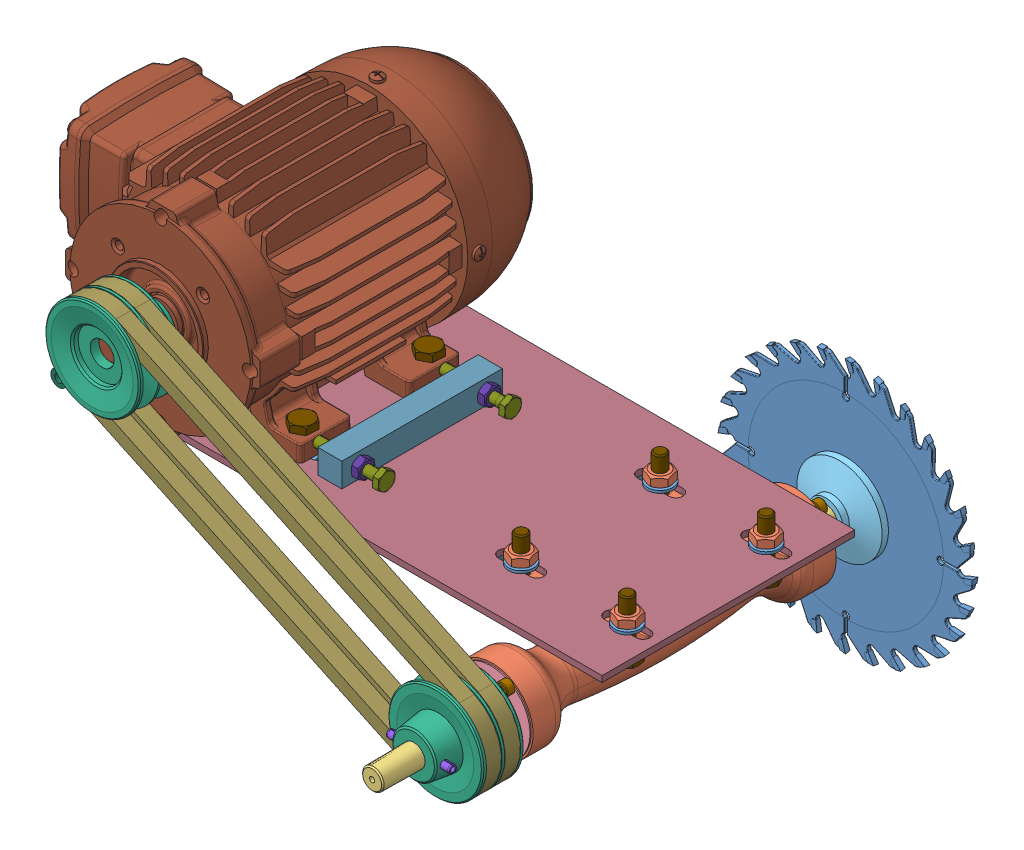
SolidWorks assembly Serra circular de bancada, configuration Default. Lengths in mm.
Overall size (508.56 311.6 431.24).
60 component instances, 20 part files, 92 mates.
Components (placement in the parent):
- cirsaw-1: cirsaw [Default] at (-60.7832 8.4139 49.2774) size (202.41 202.41 3.87)
- Eixo Serra Circular 5-8 N1-1: Eixo Serra Circular 5-8 N1 [Valor predeterminado] at (-60.7832 8.4139 212.2774) x (0 0 -1) z (-1 0 0) size (431.24 80.12 104.06)
  - Base Principal-1: Base Principal [Valor predeterminado] at origin size (240 75.12 104.06)
  - Eixo Principal-1: Eixo Principal [Valor predeterminado] at (9 0 0) size (431.24 28 28)
  - Tampa Rolamento-1: Tampa Rolamento [Valor predeterminado] at (121.5 0 0) x (0 0 1) z (-1 0 0) size (62 62 3)
  - Tampa Rolamento-2: Tampa Rolamento [Valor predeterminado] at (-121.5 0 0) x (0 0 1) z (1 0 0) size (62 62 3)
  - Suporte Principal-1: Suporte Principal [Valor predeterminado] at (152 0 0) size (16 67.5 67.5)
  - Suporte Principal-2: Suporte Principal [Valor predeterminado] at (171 0 0) x (-1 0 0) z (0 0 -1) size (16 67.5 67.5)
  - Polia Correa Dupla-1: Polia Correa Dupla [Valor predeterminado] at (-157 0 0) size (50 75 75)
  - angular contact ball bearing_68_skf_SKF - 7204 BE - 10,DE,AC,10_68-1: angular contact ball bearing_68_skf_SKF - 7204 BE - 10,DE,AC,10_68 [Valor predeterminado] at (113 0 0) size (14 47 47)
  - angular contact ball bearing_68_skf_SKF - 7204 BE - 10,DE,AC,10_68-2: angular contact ball bearing_68_skf_SKF - 7204 BE - 10,DE,AC,10_68 [Valor predeterminado] at (-113 0 0) size (14 47 47)
  - spring pin slotted_hd_din_Spring Pin ISO 8752 - 6 x 50 - N - St-1: spring pin slotted_hd_din_Spring Pin ISO 8752 - 6 x 50 - N - St [Valor predeterminado] at (-176 0 25) x (0 0 -1) z (0 -1 0) size (50 6 5.99)
  - socket head cap screw_am_B18.3.1M - 6 x 1.0 x 16 Hex SHCS -- 16SHX-1: socket head cap screw_am_B18.3.1M - 6 x 1.0 x 16 Hex SHCS -- 16SHX [Valor predeterminado] at (127 24.2487 -14) x (-1 0 0) z (0 0.924225 0.381849) size (22 10 10)
  - socket head cap screw_am_B18.3.1M - 6 x 1.0 x 16 Hex SHCS -- 16SHX-2: socket head cap screw_am_B18.3.1M - 6 x 1.0 x 16 Hex SHCS -- 16SHX [Valor predeterminado] at (127 0 28) x (-1 0 0) z (0 0.924225 0.381849) size (22 10 10)
  - socket head cap screw_am_B18.3.1M - 6 x 1.0 x 16 Hex SHCS -- 16SHX-3: socket head cap screw_am_B18.3.1M - 6 x 1.0 x 16 Hex SHCS -- 16SHX [Valor predeterminado] at (127 -24.2487 -14) x (-1 0 0) z (0 0.924225 0.381849) size (22 10 10)
  - socket head cap screw_am_B18.3.1M - 6 x 1.0 x 16 Hex SHCS -- 16SHX-4: socket head cap screw_am_B18.3.1M - 6 x 1.0 x 16 Hex SHCS -- 16SHX [Valor predeterminado] at (-127 24.2487 -14) size (22 10 10)
  - socket head cap screw_am_B18.3.1M - 6 x 1.0 x 16 Hex SHCS -- 16SHX-5: socket head cap screw_am_B18.3.1M - 6 x 1.0 x 16 Hex SHCS -- 16SHX [Valor predeterminado] at (-127 0 28) size (22 10 10)
  - socket head cap screw_am_B18.3.1M - 6 x 1.0 x 16 Hex SHCS -- 16SHX-6: socket head cap screw_am_B18.3.1M - 6 x 1.0 x 16 Hex SHCS -- 16SHX [Valor predeterminado] at (-127 -24.2487 -14) size (22 10 10)
  - hex nut heavy_am_B18.2.4.6M - Heavy hex nut,  M16 x 2 --D-S-1: hex nut heavy_am_B18.2.4.6M - Heavy hex nut,  M16 x 2 --D-S [Valor predeterminado] at (179 0 0) x (0 1 0) z (-1 0 0) size (27 31.18 17.1)
- Motor IEC  W21_GENERAL_PURPOSE  03_FRAME_80  WITH_FLANG-1: Motor IEC  W21_GENERAL_PURPOSE  03_FRAME_80  WITH_FLANG [Valor predeterminado] at (-332.4526 135.6764 223.2774) x (0 0 1) z (-1 0 0) size (300.91 163.14 218.82)
- Polia Correa Dupla-1: Polia Correa Dupla [Valor predeterminado] at (-332.4526 135.6764 352.2774) x (0 0 1) z (0 1 0) size (50 75 75)
- Correia-1: Correia [Predeterminada] at (-196.6179 72.0451 368.2774) x (0.905565 -0.424208 0) z (0 0 1) size (375 75 12)
- Correia-3: Correia [Predeterminada] at (-196.6179 72.0451 353.2774) x (0.905565 -0.424208 0) z (0 0 1) size (375 75 12)
- Base motor e eixo-1: Base motor e eixo [Predeterminada] at (-208.7832 55.6764 212.2774) x (-1 0 0) z (0 -1 0) size (430 200 4.76)
- Esticador do motor-1: Esticador do motor [Predeterminada] at (-234.2582 65.2014 223.7774) size (19.05 19.05 127)
- Gonzo fêmea-1: Gonzo fêmea [Valor predeterminado] at (-423.7832 44.5639 127.2774) x (1 0 0) z (0 0 -1) size (26.35 12.7 30)
- Gonzo fêmea-3: Gonzo fêmea [Valor predeterminado] at (-423.7832 44.5639 297.2774) x (1 0 0) z (0 0 -1) size (26.35 12.7 30)
- parafuso sextavado din 931-1 - m8 x 50-1: parafuso sextavado din 931-1 - m8 x 50 [Valor predeterminado] at (-207.9526 65.2014 273.7774) x (-1 0 0) z (0 0.832935 -0.553371) size (55.3 15.01 13)
- parafuso sextavado din 931-1 - m8 x 50-3: parafuso sextavado din 931-1 - m8 x 50 [Valor predeterminado] at (-207.9526 65.2014 173.7774) x (-1 0 0) z (0 0.832935 -0.553371) size (55.3 15.01 13)
- porca sextavada din 555-5 - m8-1: porca sextavada din 555-5 - m8 [Valor predeterminado] at (-224.7332 65.2014 173.7774) size (6.64 15.01 13)
- porca sextavada din 555-5 - m8-3: porca sextavada din 555-5 - m8 [Valor predeterminado] at (-224.7332 65.2014 273.7774) size (6.64 15.01 13)
- parafuso sextavado din 931-1 - m10 x 40-1: parafuso sextavado din 931-1 - m10 x 40 [Valor predeterminado] at (-269.9526 68.6764 173.2774) x (0 -1 0) z (0.546944 0 -0.837169) size (46.4 19.63 17)
- arruela lisa din 125 - a 10,5-1: arruela lisa din 125 - a 10,5 [Valor predeterminado] at (-269.9526 50.9139 173.2774) x (0 -1 0) z (0 0 1) size (2 20 20)
- porca sextavada din 555-5 - m10-1: porca sextavada din 555-5 - m10 [Valor predeterminado] at (-269.9526 48.9139 173.2774) x (0 -1 0) z (0 0 1) size (8 19.63 17)
- parafuso sextavado din 931-1 - m10 x 40-3: parafuso sextavado din 931-1 - m10 x 40 [Valor predeterminado] at (-269.9526 68.6764 273.2774) x (0 -1 0) z (0.546944 0 -0.837169) size (46.4 19.63 17)
- parafuso sextavado din 931-1 - m10 x 40-5: parafuso sextavado din 931-1 - m10 x 40 [Valor predeterminado] at (-394.9526 68.6764 173.2774) x (0 -1 0) z (0.983409 0 -0.181404) size (46.4 19.63 17)
- parafuso sextavado din 931-1 - m10 x 40-7: parafuso sextavado din 931-1 - m10 x 40 [Valor predeterminado] at (-394.9526 68.6764 273.2774) x (0 -1 0) z (0.546944 0 -0.837169) size (46.4 19.63 17)
- porca sextavada din 555-5 - m10-3: porca sextavada din 555-5 - m10 [Valor predeterminado] at (-394.9526 48.9139 173.2774) x (0 -1 0) z (0 0 1) size (8 19.63 17)
- porca sextavada din 555-5 - m10-5: porca sextavada din 555-5 - m10 [Valor predeterminado] at (-269.9526 48.9139 273.2774) x (0 -1 0) z (-0.269704 0 0.962943) size (8 19.63 17)
- porca sextavada din 555-5 - m10-7: porca sextavada din 555-5 - m10 [Valor predeterminado] at (-394.9526 48.9139 273.2774) x (0 -1 0) z (0 0 1) size (8 19.63 17)
- arruela lisa din 125 - a 10,5-3: arruela lisa din 125 - a 10,5 [Valor predeterminado] at (-394.9526 50.9139 173.2774) x (0 -1 0) z (0 0 1) size (2 20 20)
- arruela lisa din 125 - a 10,5-5: arruela lisa din 125 - a 10,5 [Valor predeterminado] at (-394.9526 50.9139 273.2774) x (0 -1 0) z (0 0 1) size (2 20 20)
- arruela lisa din 125 - a 10,5-7: arruela lisa din 125 - a 10,5 [Valor predeterminado] at (-269.9526 50.9139 273.2774) x (0 -1 0) z (0 0 1) size (2 20 20)
- Esticador do motor-3: Esticador do motor [Predeterminada] at (-133.3082 41.3889 212.2774) size (19.05 19.05 127)
- parafuso sextavado din 931-1 - m8 x 50-5: parafuso sextavado din 931-1 - m8 x 50 [Valor predeterminado] at (-162.7832 41.3889 162.2774) x (1 0 0) z (0 -0.387923 0.921692) size (55.3 15.01 13)
- porca sextavada din 555-5 - m8-5: porca sextavada din 555-5 - m8 [Valor predeterminado] at (-142.8332 41.3889 162.2774) x (-1 0 0) z (0 -0.924225 -0.381849) size (6.64 15.01 13)
- porca sextavada din 555-5 - m8-7: porca sextavada din 555-5 - m8 [Valor predeterminado] at (-142.8332 41.3889 262.2774) x (-1 0 0) z (0 -0.924225 -0.381849) size (6.64 15.01 13)
- parafuso sextavado din 931-1 - m8 x 50-7: parafuso sextavado din 931-1 - m8 x 50 [Valor predeterminado] at (-162.7832 41.3889 262.2774) x (1 0 0) z (0 -0.387923 0.921692) size (55.3 15.01 13)
- parafuso sextavado din 931-1 - m10 x 40-9: parafuso sextavado din 931-1 - m10 x 40 [Valor predeterminado] at (-18.7832 37.9139 267.2774) x (0 1 0) z (-0.999339 0 0.03636) size (46.4 19.63 17)
- parafuso sextavado din 931-1 - m10 x 40-11: parafuso sextavado din 931-1 - m10 x 40 [Valor predeterminado] at (-102.7832 37.9139 157.2774) x (0 1 0) z (0.414075 0 -0.910243) size (46.4 19.63 17)
- parafuso sextavado din 931-1 - m10 x 40-13: parafuso sextavado din 931-1 - m10 x 40 [Valor predeterminado] at (-102.7832 37.9139 267.2774) x (0 1 0) z (-0.996636 0 0.08195) size (46.4 19.63 17)
- parafuso sextavado din 931-1 - m10 x 40-15: parafuso sextavado din 931-1 - m10 x 40 [Valor predeterminado] at (-18.7832 37.9139 157.2774) x (0 1 0) z (-0.887169 0 0.461445) size (46.4 19.63 17)
- porca sextavada din 555-5 - m10-9: porca sextavada din 555-5 - m10 [Valor predeterminado] at (-18.7832 57.6764 267.2774) x (0 1 0) z (0.300888 0 -0.95366) size (8 19.63 17)
- porca sextavada din 555-5 - m10-11: porca sextavada din 555-5 - m10 [Valor predeterminado] at (-102.7832 57.6764 267.2774) x (0 1 0) z (0.300888 0 -0.95366) size (8 19.63 17)
- porca sextavada din 555-5 - m10-13: porca sextavada din 555-5 - m10 [Valor predeterminado] at (-102.7832 57.6764 157.2774) x (0 1 0) z (0.300888 0 -0.95366) size (8 19.63 17)
- porca sextavada din 555-5 - m10-15: porca sextavada din 555-5 - m10 [Valor predeterminado] at (-18.7832 57.6764 157.2774) x (0 1 0) z (0.300888 0 -0.95366) size (8 19.63 17)
- arruela lisa din 125 - a 10,5-9: arruela lisa din 125 - a 10,5 [Valor predeterminado] at (-102.7832 57.6764 157.2774) x (0 -1 0) z (0 0 1) size (2 20 20)
- arruela lisa din 125 - a 10,5-11: arruela lisa din 125 - a 10,5 [Valor predeterminado] at (-102.7832 57.6764 267.2774) x (0 -1 0) z (0 0 1) size (2 20 20)
- arruela lisa din 125 - a 10,5-13: arruela lisa din 125 - a 10,5 [Valor predeterminado] at (-18.7832 57.6764 267.2774) x (0 -1 0) z (0 0 1) size (2 20 20)
- arruela lisa din 125 - a 10,5-15: arruela lisa din 125 - a 10,5 [Valor predeterminado] at (-18.7832 57.6764 157.2774) x (0 -1 0) z (0 0 1) size (2 20 20)
Mates (geometry in assembly coordinates):
- Concêntrico1: concentric anti-aligned: cylinder of Motor IEC  W21_GENERAL_PURPOSE  03_FRAME_80  WITH_FLANG-1 through (-332.4526 135.6764 363.2774) axis (0 0 1) radius 9.5; cone of Polia Correa Dupla-1 through (-332.4526 135.6764 327.2774) axis (0 0 -1)
- Coincidente3: coincident anti-aligned: plane of Motor IEC  W21_GENERAL_PURPOSE  03_FRAME_80  WITH_FLANG-1 through (-332.4526 173.7764 327.2774) normal (0 0 1); plane of Polia Correa Dupla-1 through (-348.9872 152.211 327.2774) normal (0 0 -1)
- Paralelo1: parallel aligned: plane of Motor IEC  W21_GENERAL_PURPOSE  03_FRAME_80  WITH_FLANG-1 through (-332.4526 141.6764 332.2774) normal (0 1 0); plane of Polia Correa Dupla-1 through (-332.4526 135.6764 352.2774) normal (0 1 0)
- Coincidente5: coincident aligned: plane of Eixo Serra Circular 5-8 N1-1/Polia Correa Dupla-1 through (-97.7212 45.3519 377.2774) normal (0 0 1); plane of Polia Correa Dupla-1 through (-369.3906 98.7384 377.2774) normal (0 0 1)
- Concêntrico3: concentric anti-aligned: cylinder of cirsaw-1 through (-60.7832 8.4139 52.2774) axis (0 0 -1) radius 11; cylinder of Eixo Serra Circular 5-8 N1-1/Eixo Principal-1 through (-60.7832 8.4139 40.7382) axis (0 0 1) radius 8
- Coincidente6: coincident anti-aligned: plane of cirsaw-1 through (-60.7832 8.4139 52.2774) normal (0 0 1); plane of Eixo Serra Circular 5-8 N1-1/Suporte Principal-1 through (-26.6282 42.5689 52.2774) normal (0 0 -1)
- Concêntrico4: concentric anti-aligned: cylinder of Eixo Serra Circular 5-8 N1-1/Polia Correa Dupla-1 through (-60.7832 8.4139 365.5274) axis (0 0 1) radius 23.5; cylinder of Correia-1 through (-60.7832 8.4139 374.2774) axis (0 0 -1) radius 27.5
- Coincidente7: coincident anti-aligned: circle of Eixo Serra Circular 5-8 N1-1/Polia Correa Dupla-1; plane of Correia-1 through (-332.4526 135.6764 374.2774) normal (0 0 1)
- Concêntrico5: concentric aligned: cylinder of Polia Correa Dupla-1 through (-332.4526 135.6764 370.5274) axis (0 0 -1) radius 23.5; cylinder of Correia-1 through (-332.4526 135.6764 374.2774) axis (0 0 -1) radius 37.5
- Concêntrico6: concentric anti-aligned: cylinder of Eixo Serra Circular 5-8 N1-1/Polia Correa Dupla-1 through (-60.7832 8.4139 351.0274) axis (0 0 1) radius 23.5; cylinder of Correia-3 through (-60.7832 8.4139 359.2774) axis (0 0 -1) radius 27.5
- Coincidente8: coincident anti-aligned: circle of Eixo Serra Circular 5-8 N1-1/Polia Correa Dupla-1; plane of Correia-3 through (-332.4526 135.6764 347.2774) normal (0 0 -1)
- Coincidente9: coincident aligned: plane of Correia-1 through (-348.3604 101.7177 374.2774) normal (-0.424208 -0.905565 0); plane of Correia-3 through (-348.3604 101.7177 359.2774) normal (-0.424208 -0.905565 0)
- Paralelo2: parallel anti-aligned: plane of Eixo Serra Circular 5-8 N1-1/Base Principal-1 through (-10.7832 37.9139 170.0101) normal (0 -1 0); plane of assembly through (0 0 0) normal (0 1 0)
- Coincidente11: coincident anti-aligned: plane of Eixo Serra Circular 5-8 N1-1/Base Principal-1 through (-10.7832 50.9139 144.2774) normal (0 1 0); plane of Base motor e eixo-1 through (-208.7832 50.9139 212.2774) normal (0 -1 0)
- Coincidente13: coincident anti-aligned: plane of Motor IEC  W21_GENERAL_PURPOSE  03_FRAME_80  WITH_FLANG-1 through (-406.9526 55.6764 159.7774) normal (0 -1 0); plane of Base motor e eixo-1 through (-208.7832 55.6764 212.2774) normal (0 1 0)
- Coincidente14: coincident aligned: plane of Eixo Serra Circular 5-8 N1-1/Base Principal-1; plane of Base motor e eixo-1 through (-208.7832 55.6764 267.2774) normal (0 0 -1)
- Distância1: distance = 15 mm aligned: plane of Base motor e eixo-1 through (6.2168 50.9139 312.2774) normal (1 0 0); plane of Eixo Serra Circular 5-8 N1-1/Base Principal-1 through (-8.7832 48.9139 149.9199) normal (1 0 0)
- Coincidente16: coincident anti-aligned: plane of Base motor e eixo-1 through (-208.7832 55.6764 212.2774) normal (0 1 0); plane of Esticador do motor-1 through (-243.7832 55.6764 287.2774) normal (0 -1 0)
- Distância2: distance = 25 mm aligned: plane of Esticador do motor-1 through (-234.2582 65.2014 287.2774) normal (0 0 1); plane of Base motor e eixo-1 through (6.2168 50.9139 312.2774) normal (0 0 1)
- Distância3: distance = 180 mm aligned: plane of Esticador do motor-1 through (-243.7832 55.6764 287.2774) normal (-1 0 0); plane of Base motor e eixo-1 through (-423.7832 50.9139 312.2774) normal (-1 0 0)
- Coincidente17: coincident anti-aligned: plane of Base motor e eixo-1 through (-208.7832 50.9139 212.2774) normal (0 -1 0); plane of Gonzo fêmea-1 through (-423.7832 50.9139 162.5162) normal (0 1 0)
- Coincidente19: coincident aligned: plane of Base motor e eixo-1 through (6.2168 50.9139 112.2774) normal (0 0 -1); plane of Gonzo fêmea-1 through (-423.7832 44.5639 112.2774) normal (0 0 -1)
- Coincidente20: coincident anti-aligned: plane of Base motor e eixo-1 through (-423.7832 50.9139 312.2774) normal (-1 0 0); plane of Gonzo fêmea-1
- Concêntrico7: concentric aligned: cylinder of Gonzo fêmea-1 through (-423.7832 44.5639 112.2774) axis (0 0 1) radius 6.35; cylinder of Gonzo fêmea-3 through (-423.7832 44.5639 282.2774) axis (0 0 1) radius 6.35
- Coincidente22: coincident aligned: plane of Base motor e eixo-1 through (6.2168 50.9139 312.2774) normal (0 0 1); plane of Gonzo fêmea-3 through (-423.7832 44.5639 312.2774) normal (0 0 1)
- Concêntrico8: concentric anti-aligned: cylinder of Esticador do motor-1 through (-224.7332 65.2014 273.7774) axis (1 0 0) radius 3.4; cylinder of parafuso sextavado din 931-1 - m8 x 50-1 through (-246.9526 65.2014 273.7774) axis (-1 0 0) radius 4
- Coincidente23: coincident anti-aligned: plane of Motor IEC  W21_GENERAL_PURPOSE  03_FRAME_80  WITH_FLANG-1 through (-257.9526 55.6764 286.7774) normal (1 0 0); plane of parafuso sextavado din 931-1 - m8 x 50-1 through (-257.9526 66.3081 275.4433) normal (-1 0 0)
- Concêntrico9: concentric anti-aligned: cylinder of Esticador do motor-1 through (-224.7332 65.2014 173.7774) axis (1 0 0) radius 3.4; cylinder of parafuso sextavado din 931-1 - m8 x 50-3 through (-246.9526 65.2014 173.7774) axis (-1 0 0) radius 4
- Coincidente24: coincident aligned: plane of parafuso sextavado din 931-1 - m8 x 50-1 through (-202.6525 65.2014 273.7774) normal (1 0 0); plane of parafuso sextavado din 931-1 - m8 x 50-3 through (-202.6525 65.2014 173.7774) normal (1 0 0)
- Coincidente25: coincident anti-aligned: plane of Esticador do motor-1 through (-224.7332 55.6764 287.2774) normal (1 0 0); plane of porca sextavada din 555-5 - m8-1 through (-224.7332 65.2014 173.7774) normal (-1 0 0)
- Concêntrico11: concentric anti-aligned: cylinder of parafuso sextavado din 931-1 - m8 x 50-3 through (-246.9526 65.2014 173.7774) axis (-1 0 0) radius 4; cylinder of porca sextavada din 555-5 - m8-1 through (-239.1716 65.2014 173.7774) axis (1 0 0) radius 3.3235
- Coincidente26: coincident anti-aligned: plane of Esticador do motor-1 through (-224.7332 55.6764 287.2774) normal (1 0 0); plane of porca sextavada din 555-5 - m8-3 through (-224.7332 65.2014 273.7774) normal (-1 0 0)
- Concêntrico12: concentric anti-aligned: cylinder of parafuso sextavado din 931-1 - m8 x 50-1 through (-246.9526 65.2014 273.7774) axis (-1 0 0) radius 4; cylinder of porca sextavada din 555-5 - m8-3 through (-239.1716 65.2014 273.7774) axis (1 0 0) radius 3.3235
- Concêntrico13: concentric aligned: cylinder of Motor IEC  W21_GENERAL_PURPOSE  03_FRAME_80  WITH_FLANG-1 through (-269.9526 212.4789 173.2774) axis (0 -1 0) radius 5; cylinder of parafuso sextavado din 931-1 - m10 x 40-1 through (-269.9526 41.6764 173.2774) axis (0 -1 0) radius 5
- Coincidente27: coincident anti-aligned: plane of Motor IEC  W21_GENERAL_PURPOSE  03_FRAME_80  WITH_FLANG-1 through (-257.9526 68.6764 159.7774) normal (0 1 0); plane of parafuso sextavado din 931-1 - m10 x 40-1 through (-275.3104 68.6764 169.777) normal (0 -1 0)
- Coincidente28: coincident anti-aligned: plane of Base motor e eixo-1 through (-208.7832 50.9139 212.2774) normal (0 -1 0); plane of arruela lisa din 125 - a 10,5-1 through (-269.9526 50.9139 173.2774) normal (0 1 0)
- Concêntrico14: concentric aligned: cylinder of parafuso sextavado din 931-1 - m10 x 40-1 through (-269.9526 41.6764 173.2774) axis (0 -1 0) radius 5; cylinder of arruela lisa din 125 - a 10,5-1 through (-269.9526 50.9139 173.2774) axis (0 -1 0) radius 5.25
- Coincidente29: coincident anti-aligned: plane of arruela lisa din 125 - a 10,5-1 through (-269.9526 48.9139 173.2774) normal (0 -1 0); plane of porca sextavada din 555-5 - m10-1 through (-269.9526 48.9139 173.2774) normal (0 1 0)
- Concêntrico15: concentric aligned: cylinder of parafuso sextavado din 931-1 - m10 x 40-1 through (-269.9526 41.6764 173.2774) axis (0 -1 0) radius 5; cylinder of porca sextavada din 555-5 - m10-1 through (-269.9526 68.0862 173.2774) axis (0 -1 0) radius 4.188
- Concêntrico16: concentric aligned: cylinder of Motor IEC  W21_GENERAL_PURPOSE  03_FRAME_80  WITH_FLANG-1 through (-394.9526 212.4789 173.2774) axis (0 -1 0) radius 5; cylinder of parafuso sextavado din 931-1 - m10 x 40-5 through (-394.9526 41.6764 173.2774) axis (0 -1 0) radius 5
- Coincidente30: coincident aligned: plane of parafuso sextavado din 931-1 - m10 x 40-1 through (-269.9526 75.0765 173.2774) normal (0 1 0); plane of parafuso sextavado din 931-1 - m10 x 40-5 through (-394.9526 75.0765 173.2774) normal (0 1 0)
- Coincidente31: coincident aligned: plane of parafuso sextavado din 931-1 - m10 x 40-3 through (-269.9526 75.0765 273.2774) normal (0 1 0); plane of parafuso sextavado din 931-1 - m10 x 40-7 through (-394.9526 75.0765 273.2774) normal (0 1 0)
- Coincidente32: coincident aligned: plane of parafuso sextavado din 931-1 - m10 x 40-3 through (-269.9526 75.0765 273.2774) normal (0 1 0); plane of parafuso sextavado din 931-1 - m10 x 40-5 through (-394.9526 75.0765 173.2774) normal (0 1 0)
- Concêntrico17: concentric aligned: cylinder of Motor IEC  W21_GENERAL_PURPOSE  03_FRAME_80  WITH_FLANG-1 through (-394.9526 212.4789 273.2774) axis (0 -1 0) radius 5; cylinder of parafuso sextavado din 931-1 - m10 x 40-7 through (-394.9526 41.6764 273.2774) axis (0 -1 0) radius 5
- Concêntrico18: concentric aligned: cylinder of Motor IEC  W21_GENERAL_PURPOSE  03_FRAME_80  WITH_FLANG-1 through (-269.9526 212.4789 273.2774) axis (0 -1 0) radius 5; cylinder of parafuso sextavado din 931-1 - m10 x 40-3 through (-269.9526 41.6764 273.2774) axis (0 -1 0) radius 5
- Concêntrico19: concentric aligned: cylinder of parafuso sextavado din 931-1 - m10 x 40-5 through (-394.9526 41.6764 173.2774) axis (0 -1 0) radius 5; cylinder of arruela lisa din 125 - a 10,5-3 through (-394.9526 50.9139 173.2774) axis (0 -1 0) radius 5.25
- Coincidente33: coincident anti-aligned: plane of Base motor e eixo-1 through (-208.7832 50.9139 212.2774) normal (0 -1 0); plane of arruela lisa din 125 - a 10,5-3 through (-394.9526 50.9139 173.2774) normal (0 1 0)
- Coincidente34: coincident aligned: plane of arruela lisa din 125 - a 10,5-5 through (-394.9526 48.9139 273.2774) normal (0 -1 0); plane of arruela lisa din 125 - a 10,5-7 through (-269.9526 48.9139 273.2774) normal (0 -1 0)
- Coincidente35: coincident aligned: plane of arruela lisa din 125 - a 10,5-3 through (-394.9526 48.9139 173.2774) normal (0 -1 0); plane of arruela lisa din 125 - a 10,5-5 through (-394.9526 48.9139 273.2774) normal (0 -1 0)
- Concêntrico20: concentric aligned: cylinder of parafuso sextavado din 931-1 - m10 x 40-7 through (-394.9526 41.6764 273.2774) axis (0 -1 0) radius 5; cylinder of arruela lisa din 125 - a 10,5-5 through (-394.9526 50.9139 273.2774) axis (0 -1 0) radius 5.25
- Concêntrico21: concentric aligned: cylinder of parafuso sextavado din 931-1 - m10 x 40-3 through (-269.9526 41.6764 273.2774) axis (0 -1 0) radius 5; cylinder of arruela lisa din 125 - a 10,5-7 through (-269.9526 50.9139 273.2774) axis (0 -1 0) radius 5.25
- Concêntrico22: concentric aligned: cylinder of parafuso sextavado din 931-1 - m10 x 40-5 through (-394.9526 41.6764 173.2774) axis (0 -1 0) radius 5; cylinder of porca sextavada din 555-5 - m10-3 through (-394.9526 68.0862 173.2774) axis (0 -1 0) radius 4.188
- Concêntrico23: concentric aligned: cylinder of parafuso sextavado din 931-1 - m10 x 40-3 through (-269.9526 41.6764 273.2774) axis (0 -1 0) radius 5; cylinder of porca sextavada din 555-5 - m10-5 through (-269.9526 68.0862 273.2774) axis (0 -1 0) radius 4.188
- Concêntrico24: concentric aligned: cylinder of parafuso sextavado din 931-1 - m10 x 40-7 through (-394.9526 41.6764 273.2774) axis (0 -1 0) radius 5; cylinder of porca sextavada din 555-5 - m10-7 through (-394.9526 68.0862 273.2774) axis (0 -1 0) radius 4.188
- Largura1: width aligned: plane of porca sextavada din 555-5 - m10-5 through (-269.9526 40.9139 273.2774) normal (0 -1 0); plane of porca sextavada din 555-5 - m10-1 through (-269.9526 40.9139 173.2774) normal (0 -1 0); plane of porca sextavada din 555-5 - m10-3 through (-394.9526 40.9139 173.2774) normal (0 -1 0); plane of porca sextavada din 555-5 - m10-7 through (-394.9526 40.9139 273.2774) normal (0 -1 0)
- Coincidente36: coincident aligned: plane of porca sextavada din 555-5 - m10-1 through (-269.9526 40.9139 173.2774) normal (0 -1 0); plane of porca sextavada din 555-5 - m10-5 through (-269.9526 40.9139 273.2774) normal (0 -1 0)
- Coincidente37: coincident aligned: plane of porca sextavada din 555-5 - m10-1 through (-269.9526 40.9139 173.2774) normal (0 -1 0); plane of porca sextavada din 555-5 - m10-3 through (-394.9526 40.9139 173.2774) normal (0 -1 0)
- Coincidente38: coincident anti-aligned: plane of Base motor e eixo-1 through (-208.7832 50.9139 212.2774) normal (0 -1 0); plane of Esticador do motor-3 through (-142.8332 50.9139 275.7774) normal (0 1 0)
- Coincidente39: coincident anti-aligned: plane of Base motor e eixo-1; plane of Esticador do motor-3 through (-133.3082 41.3889 212.2774) normal (0 0 1)
- Coincidente40: coincident anti-aligned: plane of Esticador do motor-3 through (-142.8332 31.8639 275.7774) normal (-1 0 0); plane of porca sextavada din 555-5 - m8-5 through (-142.8332 41.3889 162.2774) normal (1 0 0)
- Concêntrico25: concentric anti-aligned: cylinder of Esticador do motor-3 through (-123.7832 41.3889 162.2774) axis (1 0 0) radius 3.4; cylinder of porca sextavada din 555-5 - m8-5 through (-128.3948 41.3889 162.2774) axis (-1 0 0) radius 3.3235
- Concêntrico26: concentric anti-aligned: cylinder of parafuso sextavado din 931-1 - m8 x 50-5 through (-123.7832 41.3889 162.2774) axis (1 0 0) radius 4; cylinder of porca sextavada din 555-5 - m8-5 through (-128.3948 41.3889 162.2774) axis (-1 0 0) radius 3.3235
- Distância4: distance = 130 mm aligned: plane of Esticador do motor-3 through (-123.7832 31.8639 275.7774) normal (1 0 0); plane of Base motor e eixo-1 through (6.2168 50.9139 312.2774) normal (1 0 0)
- Coincidente42: coincident anti-aligned: plane of Eixo Serra Circular 5-8 N1-1/Base Principal-1 through (-112.7832 48.9139 168.8533) normal (-1 0 0); plane of parafuso sextavado din 931-1 - m8 x 50-5 through (-112.7832 43.2323 163.0533) normal (1 0 0)
- Coincidente43: coincident aligned: plane of porca sextavada din 555-5 - m8-5 through (-149.3332 41.3889 162.2774) normal (-1 0 0); plane of porca sextavada din 555-5 - m8-7 through (-149.3332 41.3889 262.2774) normal (-1 0 0)
- Concêntrico27: concentric anti-aligned: cylinder of Esticador do motor-3 through (-123.7832 41.3889 262.2774) axis (1 0 0) radius 3.4; cylinder of porca sextavada din 555-5 - m8-7 through (-128.3948 41.3889 262.2774) axis (-1 0 0) radius 3.3235
- Concêntrico28: concentric anti-aligned: cylinder of porca sextavada din 555-5 - m8-7 through (-128.3948 41.3889 262.2774) axis (-1 0 0) radius 3.3235; cylinder of parafuso sextavado din 931-1 - m8 x 50-7 through (-123.7832 41.3889 262.2774) axis (1 0 0) radius 4
- Coincidente44: coincident aligned: plane of parafuso sextavado din 931-1 - m8 x 50-5 through (-168.0833 41.3889 162.2774) normal (-1 0 0); plane of parafuso sextavado din 931-1 - m8 x 50-7 through (-168.0833 41.3889 262.2774) normal (-1 0 0)
- Coincidente45: coincident anti-aligned: plane of Eixo Serra Circular 5-8 N1-1/Base Principal-1 through (-10.7832 37.9139 170.0101) normal (0 -1 0); plane of parafuso sextavado din 931-1 - m10 x 40-15 through (-21.7364 37.9139 151.5995) normal (0 1 0)
- Concêntrico29: concentric aligned: cylinder of Eixo Serra Circular 5-8 N1-1/Base Principal-1 through (-18.7832 39.9139 157.2774) axis (0 1 0) radius 5; cylinder of parafuso sextavado din 931-1 - m10 x 40-15 through (-18.7832 64.9139 157.2774) axis (0 1 0) radius 5
- Coincidente46: coincident aligned: plane of parafuso sextavado din 931-1 - m10 x 40-9 through (-18.7832 31.5138 267.2774) normal (0 -1 0); plane of parafuso sextavado din 931-1 - m10 x 40-11 through (-102.7832 31.5138 157.2774) normal (0 -1 0)
- Coincidente47: coincident aligned: plane of parafuso sextavado din 931-1 - m10 x 40-11 through (-102.7832 31.5138 157.2774) normal (0 -1 0); plane of parafuso sextavado din 931-1 - m10 x 40-13 through (-102.7832 31.5138 267.2774) normal (0 -1 0)
- Coincidente48: coincident aligned: plane of parafuso sextavado din 931-1 - m10 x 40-11 through (-102.7832 31.5138 157.2774) normal (0 -1 0); plane of parafuso sextavado din 931-1 - m10 x 40-15 through (-18.7832 31.5138 157.2774) normal (0 -1 0)
- Concêntrico30: concentric aligned: cylinder of Eixo Serra Circular 5-8 N1-1/Base Principal-1 through (-102.7832 39.9139 157.2774) axis (0 1 0) radius 5; cylinder of parafuso sextavado din 931-1 - m10 x 40-11 through (-102.7832 64.9139 157.2774) axis (0 1 0) radius 5
- Concêntrico31: concentric aligned: cylinder of Eixo Serra Circular 5-8 N1-1/Base Principal-1 through (-102.7832 39.9139 267.2774) axis (0 1 0) radius 5; cylinder of parafuso sextavado din 931-1 - m10 x 40-13 through (-102.7832 64.9139 267.2774) axis (0 1 0) radius 5
- Concêntrico32: concentric aligned: cylinder of Eixo Serra Circular 5-8 N1-1/Base Principal-1 through (-18.7832 39.9139 267.2774) axis (0 1 0) radius 5; cylinder of parafuso sextavado din 931-1 - m10 x 40-9 through (-18.7832 64.9139 267.2774) axis (0 1 0) radius 5
- Coincidente49: coincident anti-aligned: plane of porca sextavada din 555-5 - m10-15 through (-18.7832 57.6764 157.2774) normal (0 -1 0); plane of arruela lisa din 125 - a 10,5-15 through (-18.7832 57.6764 157.2774) normal (0 1 0)
- Concêntrico33: concentric anti-aligned: cylinder of porca sextavada din 555-5 - m10-15 through (-18.7832 38.5041 157.2774) axis (0 1 0) radius 4.188; cylinder of arruela lisa din 125 - a 10,5-15 through (-18.7832 57.6764 157.2774) axis (0 -1 0) radius 5.25
- Coincidente50: coincident anti-aligned: plane of Base motor e eixo-1 through (-208.7832 55.6764 212.2774) normal (0 1 0); plane of arruela lisa din 125 - a 10,5-15 through (-18.7832 55.6764 157.2774) normal (0 -1 0)
- Concêntrico34: concentric aligned: cylinder of parafuso sextavado din 931-1 - m10 x 40-15 through (-18.7832 64.9139 157.2774) axis (0 1 0) radius 5; cylinder of porca sextavada din 555-5 - m10-15 through (-18.7832 38.5041 157.2774) axis (0 1 0) radius 4.188
- Coincidente51: coincident anti-aligned: plane of porca sextavada din 555-5 - m10-9 through (-18.7832 57.6764 267.2774) normal (0 -1 0); plane of arruela lisa din 125 - a 10,5-13 through (-18.7832 57.6764 267.2774) normal (0 1 0)
- Concêntrico35: concentric anti-aligned: cylinder of porca sextavada din 555-5 - m10-9 through (-18.7832 38.5041 267.2774) axis (0 1 0) radius 4.188; cylinder of arruela lisa din 125 - a 10,5-13 through (-18.7832 57.6764 267.2774) axis (0 -1 0) radius 5.25
- Coincidente52: coincident anti-aligned: plane of Base motor e eixo-1 through (-208.7832 55.6764 212.2774) normal (0 1 0); plane of arruela lisa din 125 - a 10,5-13 through (-18.7832 55.6764 267.2774) normal (0 -1 0)
- Concêntrico36: concentric aligned: cylinder of parafuso sextavado din 931-1 - m10 x 40-9 through (-18.7832 64.9139 267.2774) axis (0 1 0) radius 5; cylinder of porca sextavada din 555-5 - m10-9 through (-18.7832 38.5041 267.2774) axis (0 1 0) radius 4.188
- Coincidente53: coincident anti-aligned: plane of porca sextavada din 555-5 - m10-11 through (-102.7832 57.6764 267.2774) normal (0 -1 0); plane of arruela lisa din 125 - a 10,5-11 through (-102.7832 57.6764 267.2774) normal (0 1 0)
- Concêntrico37: concentric anti-aligned: cylinder of porca sextavada din 555-5 - m10-11 through (-102.7832 38.5041 267.2774) axis (0 1 0) radius 4.188; cylinder of arruela lisa din 125 - a 10,5-11 through (-102.7832 57.6764 267.2774) axis (0 -1 0) radius 5.25
- Coincidente54: coincident anti-aligned: plane of Base motor e eixo-1 through (-208.7832 55.6764 212.2774) normal (0 1 0); plane of arruela lisa din 125 - a 10,5-11 through (-102.7832 55.6764 267.2774) normal (0 -1 0)
- Concêntrico38: concentric aligned: cylinder of parafuso sextavado din 931-1 - m10 x 40-13 through (-102.7832 64.9139 267.2774) axis (0 1 0) radius 5; cylinder of porca sextavada din 555-5 - m10-11 through (-102.7832 38.5041 267.2774) axis (0 1 0) radius 4.188
- Coincidente55: coincident anti-aligned: plane of porca sextavada din 555-5 - m10-13 through (-102.7832 57.6764 157.2774) normal (0 -1 0); plane of arruela lisa din 125 - a 10,5-9 through (-102.7832 57.6764 157.2774) normal (0 1 0)
- Concêntrico39: concentric anti-aligned: cylinder of porca sextavada din 555-5 - m10-13 through (-102.7832 38.5041 157.2774) axis (0 1 0) radius 4.188; cylinder of arruela lisa din 125 - a 10,5-9 through (-102.7832 57.6764 157.2774) axis (0 -1 0) radius 5.25
- Coincidente56: coincident anti-aligned: plane of Base motor e eixo-1 through (-208.7832 55.6764 212.2774) normal (0 1 0); plane of arruela lisa din 125 - a 10,5-9 through (-102.7832 55.6764 157.2774) normal (0 -1 0)
- Concêntrico40: concentric aligned: cylinder of parafuso sextavado din 931-1 - m10 x 40-11 through (-102.7832 64.9139 157.2774) axis (0 1 0) radius 5; cylinder of porca sextavada din 555-5 - m10-13 through (-102.7832 38.5041 157.2774) axis (0 1 0) radius 4.188
